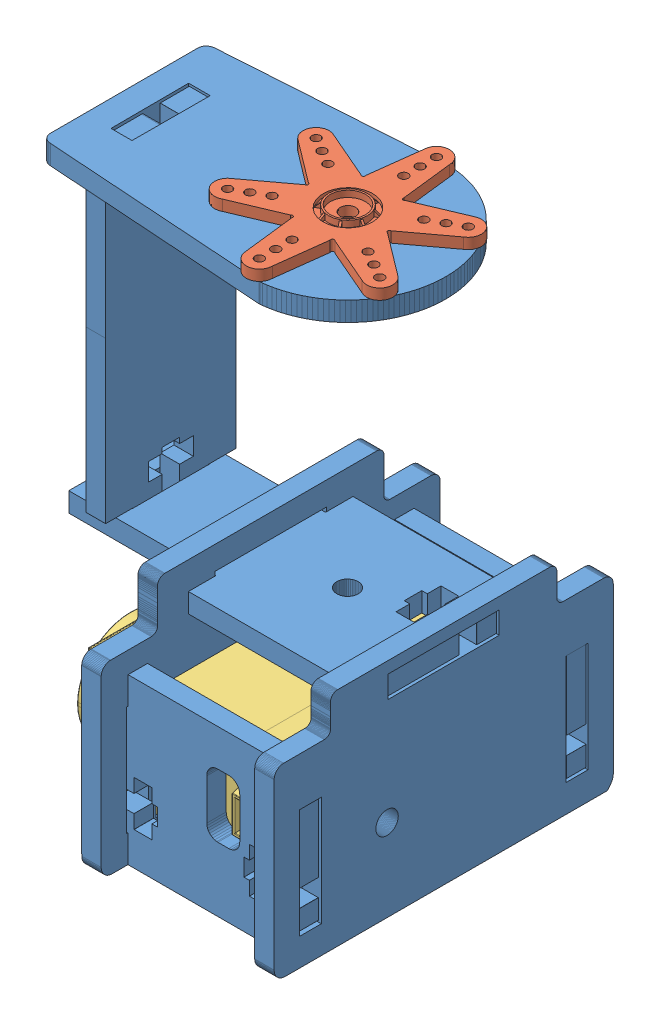
SolidWorks assembly Assem5, configuration Default. Lengths in mm.
Overall size (64.15 97.43 61.04).
4 component instances, 3 part files, 2 mates.
Components (placement in the parent):
- right_hip100-1: right_hip100 [Default] at origin size (57.95 94.99 61.04)
- servo_arm_6_sided-1: servo_arm_6_sided [Default] at (41.5039 95.3782 30.328) x (-0.86809 0 0.496406) z (-0.496406 0 -0.86809) size (36.45 6.25 32.2)
- main_assembly-1: main_assembly [Default] at (82.8661 30.8949 -3.4568) x (0.000102 -1 0) z (-1 -0.000102 0) size (20 53 41.5)
  - main_body-1: main_body [Default] at (15.1003 34.2066 38.7045) size (20 53 41.5)
Mates (geometry in assembly coordinates):
- ProfileCenter1: profile center anti-aligned: circle of right_hip100-1; circle of servo_arm_6_sided-1
- Coincident1: coincident anti-aligned: line of right_hip100-1 through (24.1621 25.7886 9.6951) axis (0 0 1); line of main_assembly-1/main_body-1 through (24.1621 25.7886 50.4997) axis (0 0 -1)
